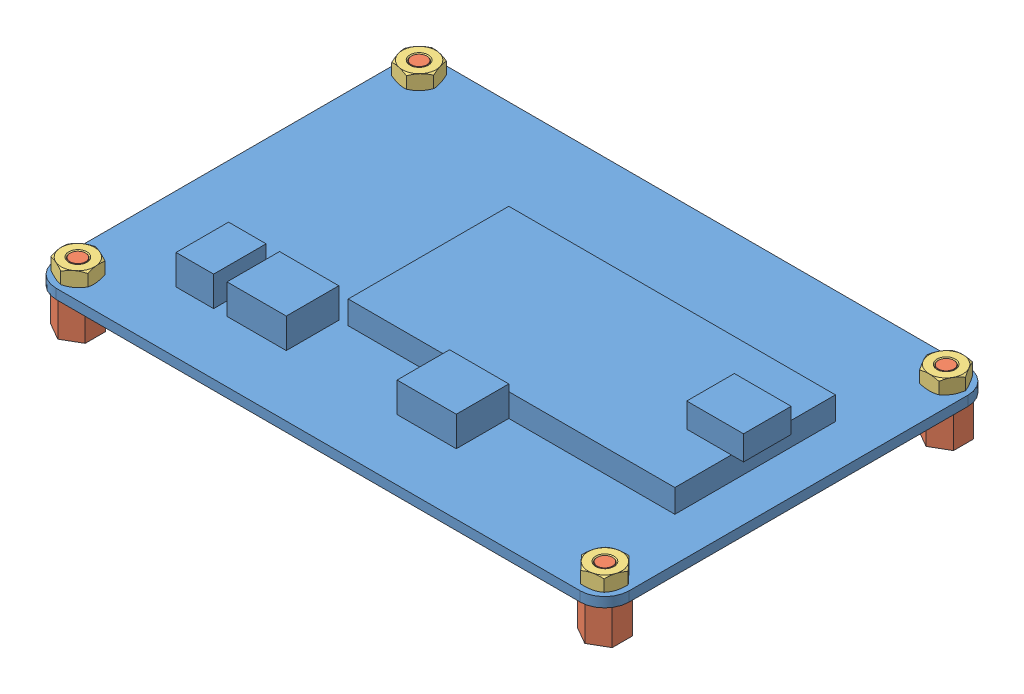
SolidWorks assembly logic-pcb-with-spacers, configuration Default. Lengths in mm.
Overall size (94.78 15.4 64.22).
9 component instances, 3 part files, 20 mates.
Components (placement in the parent):
- logic-pcb-1: logic-pcb [Default] at origin size (93.85 9.4 63.5)
- pcb-spacer-6mm-1: pcb-spacer-6mm [Default] at (-43.1625 -6 27.95) x (0.866025 0 -0.5) z (0.5 0 0.866025) size (6.58 9.95 5.7)
- hex nut style 1_am-1: hex nut style 1_am [B18.2.4.1M - Hex nut, Style 1,  M3 x 0.5 --D-C] at (-43.1625 4 27.95) x (0.993884 0 -0.110433) z (0 1 0) size (5.5 6.35 2.4)
- pcb-spacer-6mm-2: pcb-spacer-6mm [Default] at (-43.1625 -6 -27.95) x (0.866025 0 -0.5) z (0.5 0 0.866025) size (6.58 9.95 5.7)
- hex nut style 1_am-2: hex nut style 1_am [B18.2.4.1M - Hex nut, Style 1,  M3 x 0.5 --D-C] at (-43.1625 4 -27.95) x (0.955263 0 -0.295757) z (0 1 0) size (5.5 6.35 2.4)
- pcb-spacer-6mm-3: pcb-spacer-6mm [Default] at (43.1625 -6 -27.95) x (0 0 -1) z (1 0 0) size (6.58 9.95 5.7)
- hex nut style 1_am-3: hex nut style 1_am [B18.2.4.1M - Hex nut, Style 1,  M3 x 0.5 --D-C] at (43.1625 4 -27.95) x (0.869046 0 -0.494732) z (0 1 0) size (5.5 6.35 2.4)
- pcb-spacer-6mm-4: pcb-spacer-6mm [Default] at (43.1625 -6 27.95) x (0 0 -1) z (1 0 0) size (6.58 9.95 5.7)
- hex nut style 1_am-4: hex nut style 1_am [B18.2.4.1M - Hex nut, Style 1,  M3 x 0.5 --D-C] at (43.1625 4 27.95) x (0.728847 0 -0.684677) z (0 1 0) size (5.5 6.35 2.4)
Mates (geometry in assembly coordinates):
- Concentric1: concentric aligned: cylinder of logic-pcb-1 through (-43.1625 1.6 27.95) axis (0 -1 0) radius 1.65; cylinder of pcb-spacer-6mm-1 through (-43.1625 3.95 27.95) axis (0 -1 0) radius 1.45
- Coincident1: coincident anti-aligned: plane of logic-pcb-1 through (0 0 0) normal (0 -1 0); plane of pcb-spacer-6mm-1 through (-43.1625 0 27.95) normal (0 1 0)
- Concentric2: concentric anti-aligned: cylinder of pcb-spacer-6mm-1 through (-43.1625 3.95 27.95) axis (0 -1 0) radius 1.45; cylinder of hex nut style 1_am-1 through (-43.1625 1.6 27.95) axis (0 1 0) radius 1.25
- Coincident2: coincident anti-aligned: plane of logic-pcb-1 through (0 1.6 0) normal (0 1 0); plane of hex nut style 1_am-1 through (-43.5132 1.6 24.794) normal (0 -1 0)
- Concentric3: concentric anti-aligned: cylinder of pcb-spacer-6mm-2 through (-43.1625 3.95 -27.95) axis (0 -1 0) radius 1.45; cylinder of hex nut style 1_am-2 through (-43.1625 1.6 -27.95) axis (0 1 0) radius 1.25
- Concentric4: concentric aligned: cylinder of logic-pcb-1 through (-43.1625 1.6 -27.95) axis (0 -1 0) radius 1.65; cylinder of pcb-spacer-6mm-2 through (-43.1625 3.95 -27.95) axis (0 -1 0) radius 1.45
- Coincident3: coincident anti-aligned: plane of logic-pcb-1 through (0 0 0) normal (0 -1 0); plane of pcb-spacer-6mm-2 through (-43.1625 0 -27.95) normal (0 1 0)
- Coincident4: coincident anti-aligned: plane of logic-pcb-1 through (0 1.6 0) normal (0 1 0); plane of hex nut style 1_am-2 through (-44.1017 1.6 -30.9834) normal (0 -1 0)
- Concentric5: concentric anti-aligned: cylinder of pcb-spacer-6mm-3 through (43.1625 3.95 -27.95) axis (0 -1 0) radius 1.45; cylinder of hex nut style 1_am-3 through (43.1625 1.6 -27.95) axis (0 1 0) radius 1.25
- Coincident5: coincident anti-aligned: plane of logic-pcb-1 through (0 0 0) normal (0 -1 0); plane of pcb-spacer-6mm-3 through (43.1625 0 -27.95) normal (0 1 0)
- Coincident6: coincident anti-aligned: plane of logic-pcb-1 through (0 1.6 0) normal (0 1 0); plane of hex nut style 1_am-3 through (41.5915 1.6 -30.7096) normal (0 -1 0)
- Concentric6: concentric aligned: cylinder of logic-pcb-1 through (43.1625 1.6 -27.95) axis (0 -1 0) radius 1.65; cylinder of pcb-spacer-6mm-3 through (43.1625 3.95 -27.95) axis (0 -1 0) radius 1.45
- Concentric7: concentric anti-aligned: cylinder of pcb-spacer-6mm-4 through (43.1625 3.95 27.95) axis (0 -1 0) radius 1.45; cylinder of hex nut style 1_am-4 through (43.1625 1.6 27.95) axis (0 1 0) radius 1.25
- Coincident7: coincident anti-aligned: plane of logic-pcb-1 through (0 0 0) normal (0 -1 0); plane of pcb-spacer-6mm-4 through (43.1625 0 27.95) normal (0 1 0)
- Coincident8: coincident anti-aligned: plane of logic-pcb-1 through (0 1.6 0) normal (0 1 0); plane of hex nut style 1_am-4 through (40.9884 1.6 25.6356) normal (0 -1 0)
- Concentric8: concentric aligned: cylinder of logic-pcb-1 through (43.1625 1.6 27.95) axis (0 -1 0) radius 1.65; cylinder of pcb-spacer-6mm-4 through (43.1625 3.95 27.95) axis (0 -1 0) radius 1.45
- Parallel1: parallel aligned: plane of logic-pcb-1 through (-46.925 1.6 -31.75) normal (-1 0 0); plane of pcb-spacer-6mm-2 through (-46.0125 -1 -29.5954) normal (-1 0 0)
- Parallel2: parallel aligned: plane of logic-pcb-1 through (-46.925 1.6 -31.75) normal (-1 0 0); plane of pcb-spacer-6mm-1 through (-46.0125 -1 26.3046) normal (-1 0 0)
- Parallel3: parallel aligned: plane of logic-pcb-1 through (46.925 1.6 -31.75) normal (1 0 0); plane of pcb-spacer-6mm-4 through (46.0125 -1 29.5954) normal (1 0 0)
- Parallel4: parallel aligned: plane of logic-pcb-1 through (46.925 1.6 -31.75) normal (1 0 0); plane of pcb-spacer-6mm-3 through (46.0125 -1 -26.3046) normal (1 0 0)
